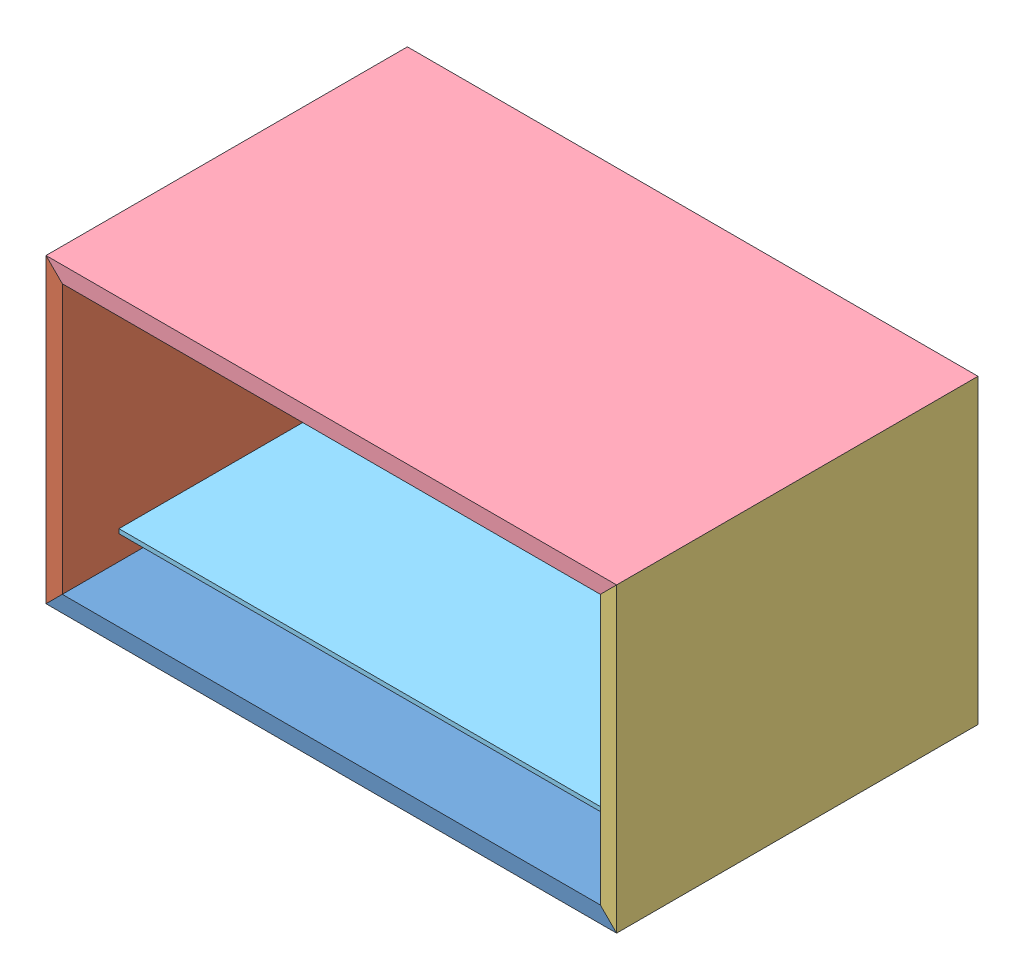
SolidWorks assembly UberRadio, configuration Default. Lengths in mm.
Overall size (210 111 133).
5 component instances, 5 part files, 9 mates.
Components (placement in the parent):
- UberRadio_Bottom-1: UberRadio_Bottom [Default] at (62.7522 87.5087 186.483) x (1 0 0) z (0 0 -1) size (210 6 133)
- UberRadio_Left_Side-1: UberRadio_Left_Side [Default] at (-36.2478 137.0087 186.483) x (0 1 0) z (0 0 1) size (111 6 133)
- UberRadio_Right_Side-1: UberRadio_Right_Side [Default] at (161.7522 137.0087 186.483) x (0 -1 0) z (0 0 1) size (111 6 133)
- UberRadio_Top-1: UberRadio_Top [Default] at (62.7522 186.5087 186.483) size (210 6 133)
- Powr_Board-1: Powr_Board [Default] at (63.3277 105.99 186.7057) size (180 1.6 110)
Mates (geometry in assembly coordinates):
- Coincident1: coincident anti-aligned: plane of UberRadio_Bottom-1 through (-36.2478 87.5087 186.483) normal (-0.707107 0.707107 0); plane of UberRadio_Left_Side-1 through (-36.2478 87.5087 186.483) normal (0.707107 -0.707107 0)
- Coincident2: coincident anti-aligned: plane of UberRadio_Left_Side-1 through (-42.2478 192.5087 252.983) normal (0.707107 0.707107 0); plane of UberRadio_Top-1 through (-36.2478 186.5087 186.483) normal (-0.707107 -0.707107 0)
- Coincident3: coincident anti-aligned: plane of UberRadio_Bottom-1 through (167.7522 81.5087 119.983) normal (0.707107 0.707107 0); plane of UberRadio_Right_Side-1 through (167.7522 81.5087 252.983) normal (-0.707107 -0.707107 0)
- Coincident4: coincident anti-aligned: line of UberRadio_Bottom-1 through (-42.2478 81.5087 119.983) axis (0 0 1); line of UberRadio_Left_Side-1 through (-42.2478 81.5087 252.983) axis (0 0 -1)
- Coincident5: coincident aligned: line of UberRadio_Left_Side-1 through (-42.2478 192.5087 252.983) axis (0 0 -1); line of UberRadio_Top-1 through (-42.2478 192.5087 252.983) axis (0 0 -1)
- Coincident6: coincident anti-aligned: line of UberRadio_Bottom-1 through (167.7522 81.5087 119.983) axis (0 0 1); line of UberRadio_Right_Side-1 through (167.7522 81.5087 252.983) axis (0 0 -1)
- Coincident7: coincident aligned: plane of UberRadio_Right_Side-1 through (167.7522 192.5087 252.983) normal (0 0 1); plane of UberRadio_Top-1 through (-42.2478 192.5087 252.983) normal (0 0 1)
- Coincident8: coincident aligned: plane of UberRadio_Bottom-1 through (-42.2478 81.5087 252.983) normal (0 0 1); plane of UberRadio_Right_Side-1 through (167.7522 192.5087 252.983) normal (0 0 1)
- Coincident9: coincident aligned: plane of UberRadio_Left_Side-1 through (-42.2478 81.5087 252.983) normal (0 0 1); plane of UberRadio_Top-1 through (-42.2478 192.5087 252.983) normal (0 0 1)
